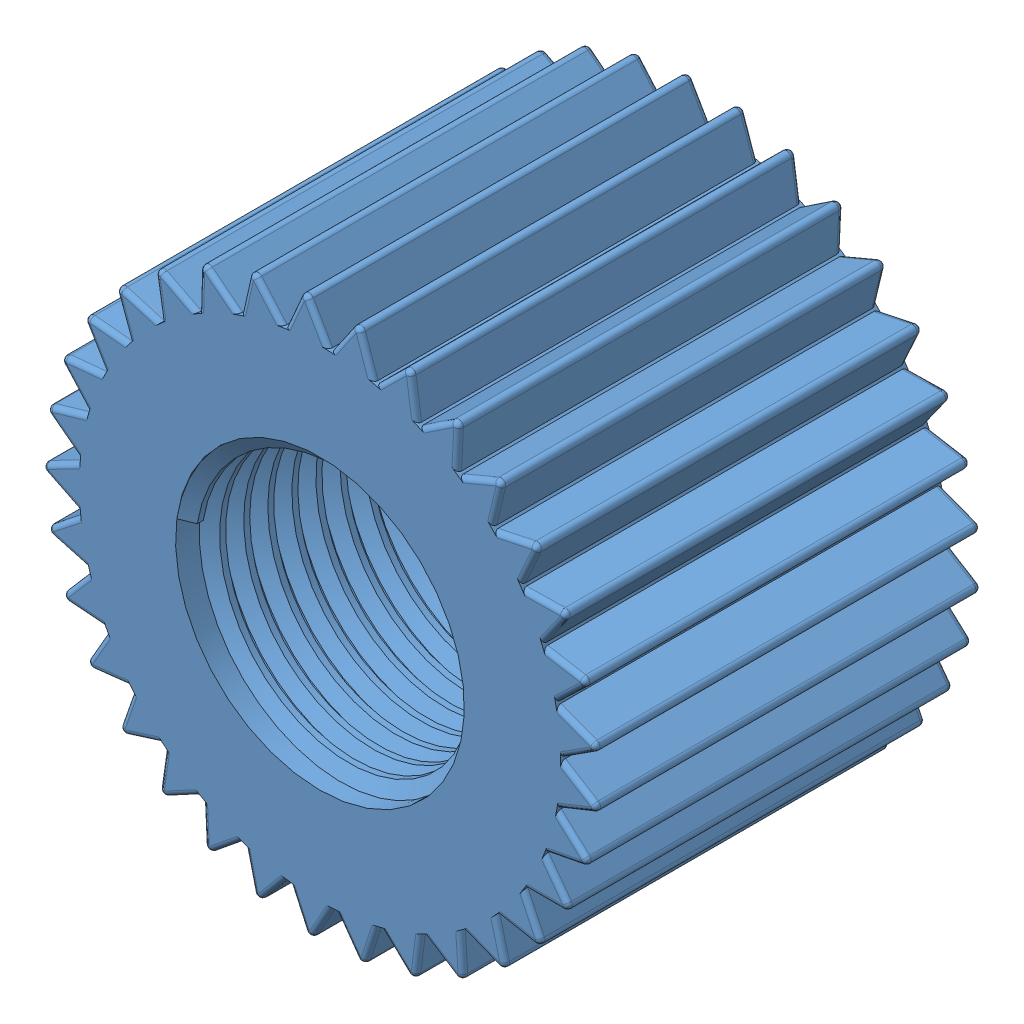
SolidWorks assembly main_assembly (mg996r), configuration Default. Lengths in mm.
Overall size (20 53 44.5).
2 component instances, 2 part files, 2 mates.
Components (placement in the parent):
- main_body (re)-1: main_body (re) [Default] at (15.1003 34.2066 38.7045)
- gear-1: gear [Default] at (15.0988 44.3995 70.2045) x (0.991102 -0.133104 0) z (0 0 1)
Mates (geometry in assembly coordinates):
- Concentric1: concentric aligned: circle of main_body (re)-1; circle of gear-1
- Coincident2: coincident anti-aligned: plane of main_body (re)-1 through (15.0988 44.3995 70.2045) normal (0 0 1); plane of gear-1 through (15.0988 44.3995 70.2045) normal (0 0 -1)
